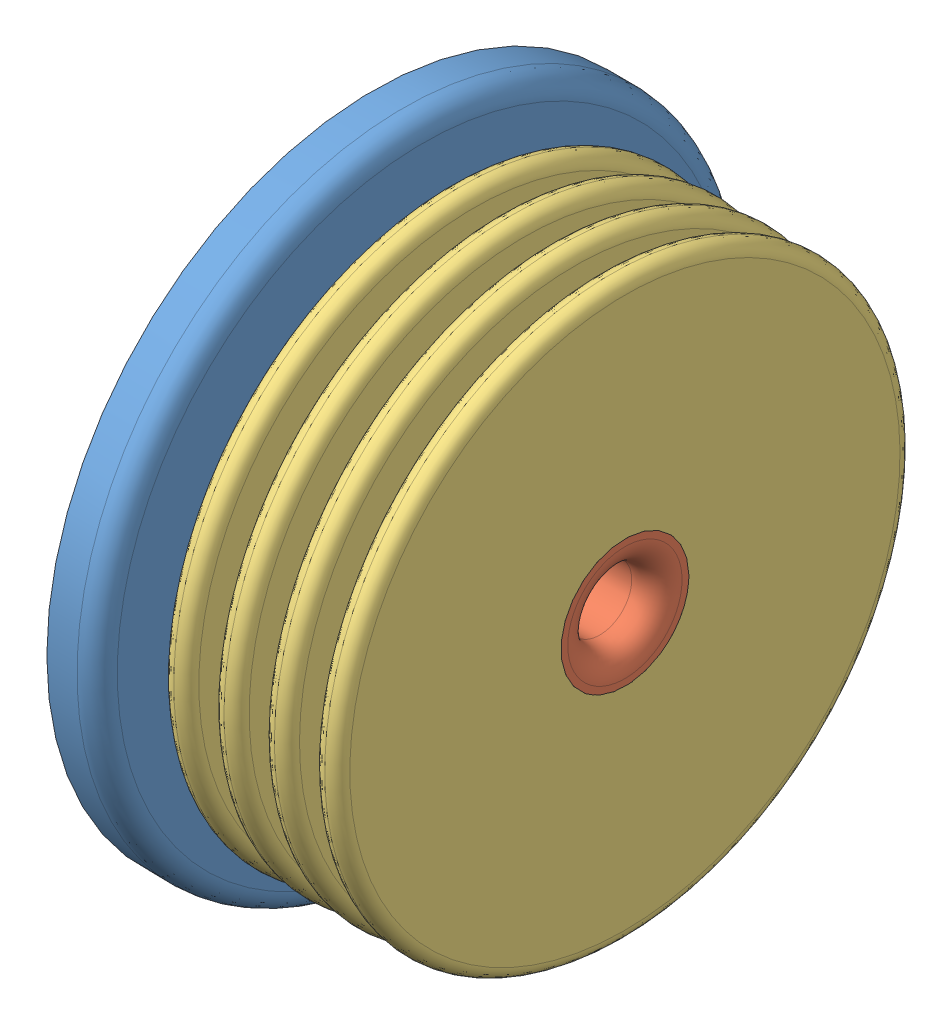
SolidWorks assembly heatsinkassem, configuration Default. Lengths in mm.
Overall size (60 145.3 145.3).
6 component instances, 3 part files, 9 mates.
Components (placement in the parent):
- heatsinkcaps-1: heatsinkcaps [Default] at (-29.5271 64.3291 142.9598) size (20 129.7 129.7)
- heatsinkbar-1: heatsinkbar [Default] at (-19.5271 64.3291 142.9598) size (50 25.4 25.4)
- heatsinkdisc-1: heatsinkdisc [Default] at (-4.5271 64.3291 142.9598) x (1 0 0) z (0 -0.002531 0.999997) size (5 114.3 114.3)
- heatsinkdisc-2: heatsinkdisc [Default] at (5.4729 64.3291 142.9598) x (1 0 0) z (0 -0.32571 0.94547) size (5 114.3 114.3)
- heatsinkdisc-3: heatsinkdisc [Default] at (15.4729 64.3291 142.9598) x (1 0 0) z (0 -0.122449 0.992475) size (5 114.3 114.3)
- heatsinkdisc-4: heatsinkdisc [Default] at (25.4729 64.3291 142.9598) x (1 0 0) z (0 -0.013398 0.99991) size (5 114.3 114.3)
Mates (geometry in assembly coordinates):
- Coincident1: coincident aligned: circle of heatsinkcaps-1; circle of heatsinkbar-1
- Concentric2: concentric anti-aligned: cylinder of heatsinkbar-1 through (30.4729 64.3291 142.9598) axis (-1 0 0) radius 12.7; cylinder of heatsinkdisc-1 through (-4.5271 64.3291 142.9598) axis (1 0 0) radius 12.7
- Concentric3: concentric anti-aligned: cylinder of heatsinkbar-1 through (30.4729 64.3291 142.9598) axis (-1 0 0) radius 12.7; cylinder of heatsinkdisc-2 through (5.4729 64.3291 142.9598) axis (1 0 0) radius 12.7
- Concentric4: concentric anti-aligned: cylinder of heatsinkbar-1 through (30.4729 64.3291 142.9598) axis (-1 0 0) radius 12.7; cylinder of heatsinkdisc-3 through (15.4729 64.3291 142.9598) axis (1 0 0) radius 12.7
- Concentric5: concentric anti-aligned: cylinder of heatsinkbar-1 through (30.4729 64.3291 142.9598) axis (-1 0 0) radius 12.7; cylinder of heatsinkdisc-4 through (25.4729 64.3291 142.9598) axis (1 0 0) radius 12.7
- Distance1: distance = 5 mm anti-aligned: plane of heatsinkcaps-1 through (-9.5271 64.3291 142.9598) normal (1 0 0); plane of heatsinkdisc-1 through (-4.5271 64.3291 142.9598) normal (-1 0 0)
- Distance2: distance = 15 mm anti-aligned: plane of heatsinkcaps-1 through (-9.5271 64.3291 142.9598) normal (1 0 0); plane of heatsinkdisc-2 through (5.4729 64.3291 142.9598) normal (-1 0 0)
- Distance3: distance = 25 mm anti-aligned: plane of heatsinkcaps-1 through (-9.5271 64.3291 142.9598) normal (1 0 0); plane of heatsinkdisc-3 through (15.4729 64.3291 142.9598) normal (-1 0 0)
- Distance4: distance = 35 mm anti-aligned: plane of heatsinkcaps-1 through (-9.5271 64.3291 142.9598) normal (1 0 0); plane of heatsinkdisc-4 through (25.4729 64.3291 142.9598) normal (-1 0 0)
